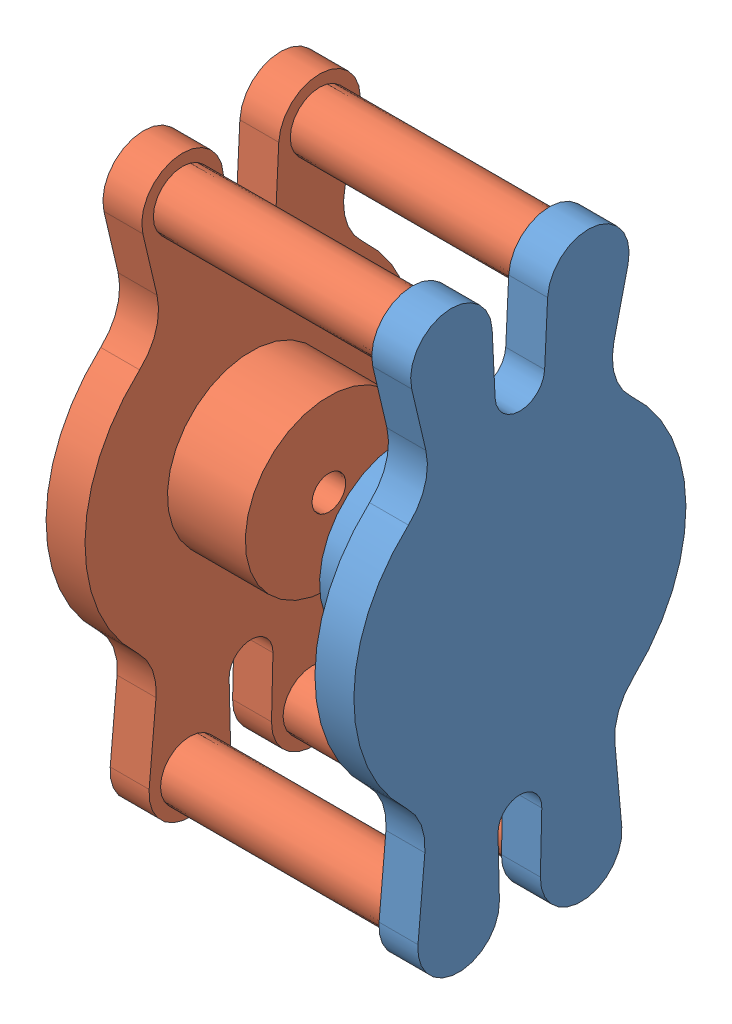
SolidWorks assembly Assem1, configuration Default. Lengths in mm.
Overall size (67.79 127.51 73.15).
2 component instances, 2 part files, 3 mates.
Components (placement in the parent):
- plate_attachment3-1: plate_attachment3 [Default] at (-48.7635 23.79 -29.2685) size (59.17 127.51 73.15)
- plate_attachment2-1: plate_attachment2 [Default] at (-48.6087 23.79 -29.2685) x (-1 0 0) z (0 0 -1) size (59.22 127.51 73.15)
Mates (geometry in assembly coordinates):
- Concentric1: concentric: cylinder of plate_attachment3-1 through (-73.9591 78.5587 -44.3497) axis (1 0 0) radius 4.549; cylinder of plate_attachment2-1 through (-85.1529 78.5587 -44.3497) axis (-1 0 0) radius 4.7474
- Concentric2: concentric: cylinder of plate_attachment3-1 through (-73.9591 -30.9788 -15.7747) axis (1 0 0) radius 4.549; cylinder of plate_attachment2-1 through (-85.1529 -30.9788 -15.7747) axis (-1 0 0) radius 4.7474
- Coincident1: coincident anti-aligned: plane of plate_attachment3-1 through (-23.3635 23.79 -29.2685) normal (-1 0 0); plane of plate_attachment2-1 through (-23.3635 78.5587 -44.3497) normal (1 0 0)
